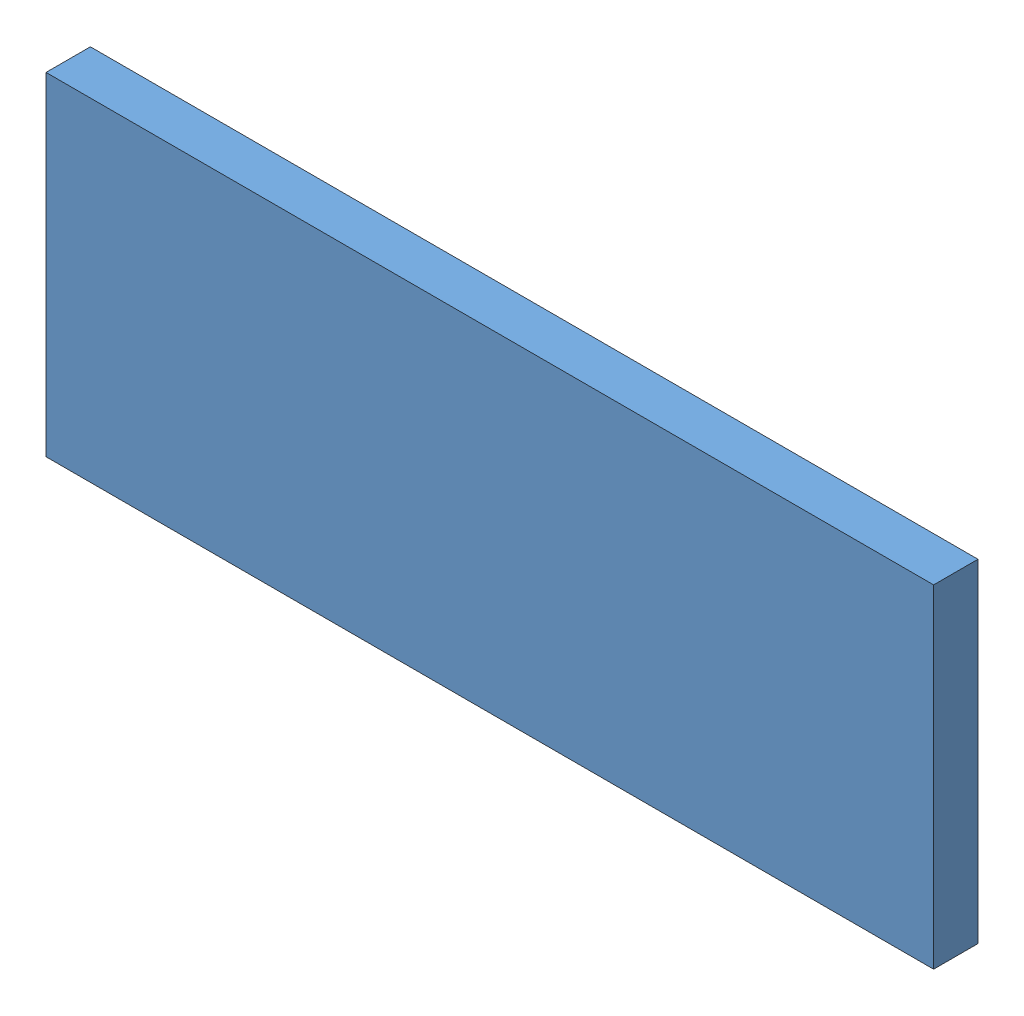
SolidWorks assembly Capacitor Test Assembly, configuration Default. Lengths in mm.
Overall size (80 30 4).
3 component instances, 3 part files, 0 mates.
Components (placement in the parent):
- Capacitor Test - Body-1: Capacitor Test - Body [Default] at (35.523 51.1552 76.4107) size (80 30 4)
- Capacitor Test - Capacitors-1: Capacitor Test - Capacitors [Default] at (35.523 51.1552 79.4107) size (70 15 0.25)
- Capacitor Test - Pads-1: Capacitor Test - Pads [Default] at (35.523 51.1552 79.4107) size (70 30 0.75)
